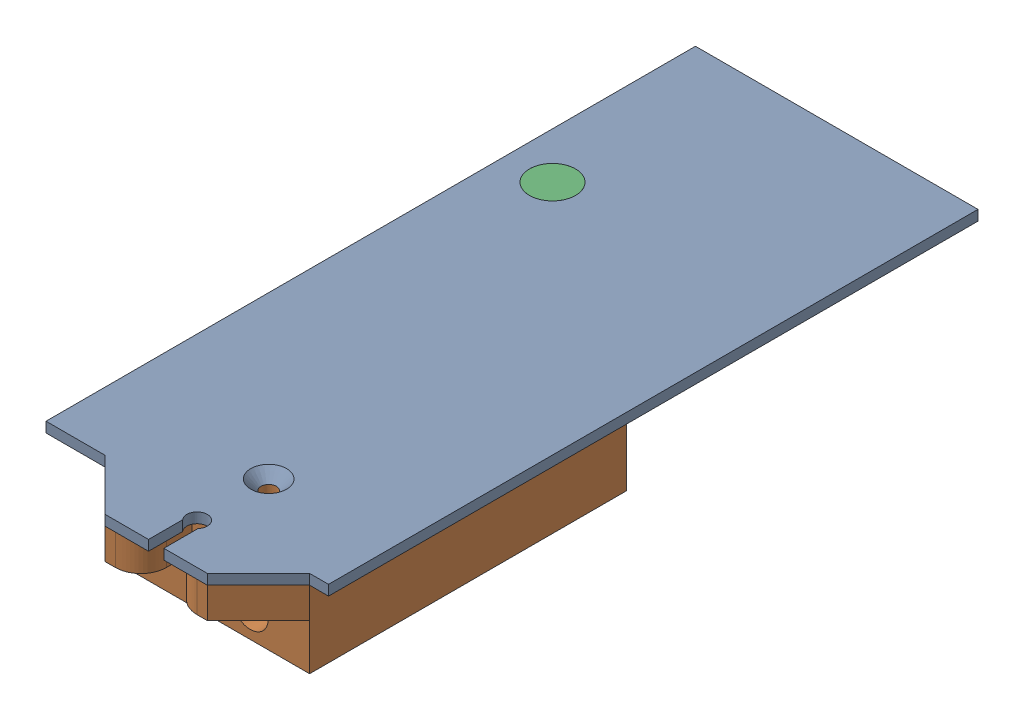
SolidWorks assembly SE_Clampeur Caisse, configuration Défaut. Lengths in mm.
Overall size (55.25 25 137).
3 component instances, 3 part files, 5 mates.
Components (placement in the parent):
- SE_Clampeur Caisse ossature-1: SE_Clampeur Caisse ossature [Défaut] at (40.4583 -64.6986 46.9838) size (55.25 2 137)
- Bloc clampeur-1: Bloc clampeur [Défaut] at (-245.5417 121.3014 142.9838) x (0 0 1) z (0 -1 0) size (72 40 15)
- Goujon sertir D5-L25-2: Goujon sertir D5-L25 [Défaut] at (-268.0417 123.3014 83.9838) x (0 1 0) z (0 0 1) size (25 9 9)
Mates (geometry in assembly coordinates):
- Coaxiale1: concentric anti-aligned: cone of SE_Clampeur Caisse ossature-1 through (-245.5417 123.3014 161.9838) axis (0 -1 0); cylinder of Bloc clampeur-1 through (-245.5417 106.3014 161.9838) axis (0 1 0) radius 1.6
- Coïncidente1: coincident anti-aligned: plane of SE_Clampeur Caisse ossature-1 through (40.4583 121.3014 183.9838) normal (0 -1 0); plane of Bloc clampeur-1 through (-225.5417 121.3014 111.9838) normal (0 1 0)
- Coïncidente4: coincident anti-aligned: circle of SE_Clampeur Caisse ossature-1; plane of Goujon sertir D5-L25-2 through (-272.5417 123.3014 83.9838) normal (0 1 0)
- Coïncidente5: coincident aligned: plane of SE_Clampeur Caisse ossature-1 through (42.4583 123.3014 183.9838) normal (0 1 0); plane of Goujon sertir D5-L25-2 through (-272.5417 123.3014 83.9838) normal (0 1 0)
- Coïncidente7: coincident aligned: circle of SE_Clampeur Caisse ossature-1; circle of Goujon sertir D5-L25-2
